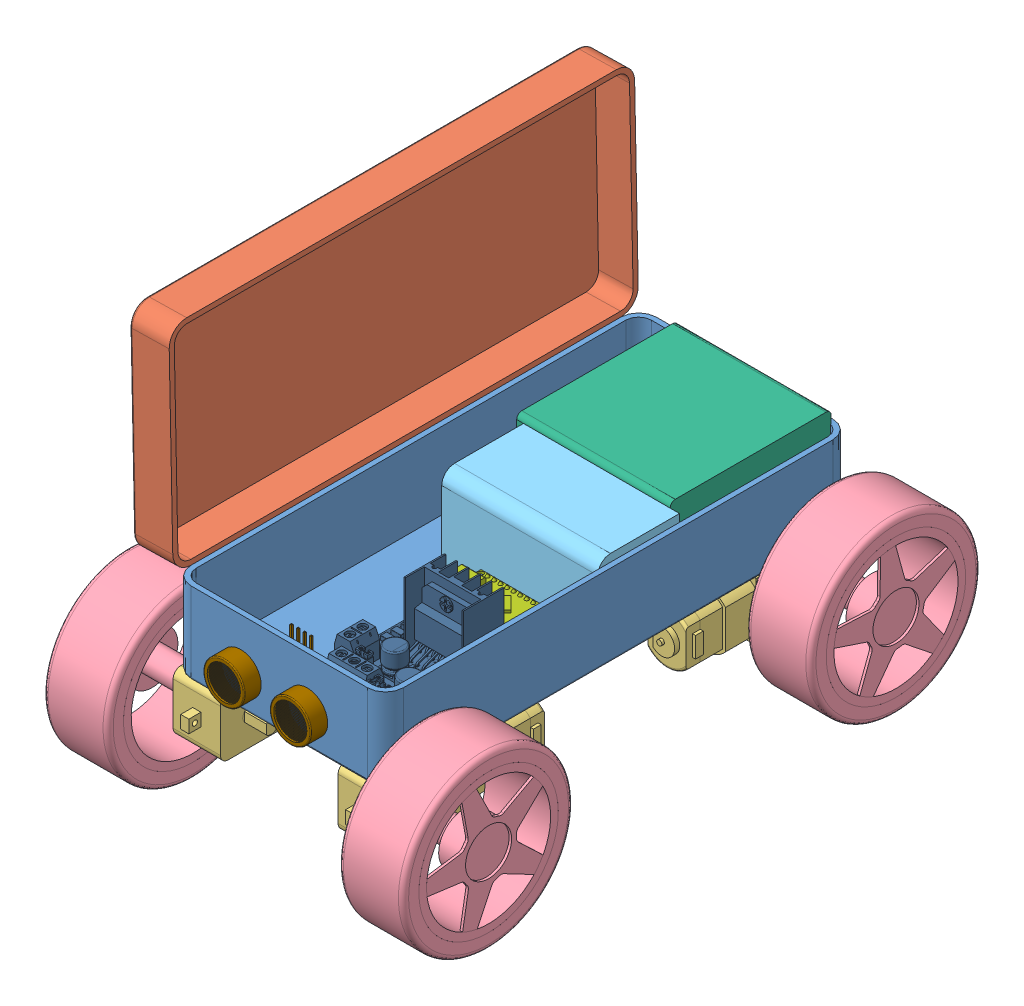
SolidWorks assembly Сборка1, configuration По умолчанию. Lengths in mm.
Overall size (141 168.35 238.58).
16 component instances, 10 part files, 33 mates.
Components (placement in the parent):
- Деталь1-1: Деталь1 [По умолчанию] at origin size (83 32 182)
- Деталь2-1: Деталь2 [По умолчанию] at (-84.679 114.983 0) x (-0.020229 0.999795 0) z (0 0 1) size (83 15.5 182)
- motor-1: motor [Predeterminado] at (-73.75 -11.35 -18.5) x (0 0 1) z (1 0 0) size (71.1 22.7 38)
- llanta-1: llanta [Predeterminado] at (-112 -11.35 -11.35) x (0 -0.972916 0.231159) z (-1 0 0) size (66.5 66.5 29)
- llanta-2: llanta [Predeterminado] at (29 -11.35 -11.35) x (0 0.314264 -0.949335) z (1 0 0) size (66.5 66.5 29)
- motor-2: motor [Predeterminado] at (-9.25 -11.35 -18.5) x (0 0 1) z (-1 0 0) size (71.1 22.7 38)
- motor-3: motor [Predeterminado] at (-9.25 -11.35 -163.5) x (0 0 -1) z (-1 0 0) size (71.1 22.7 38)
- llanta-3: llanta [Predeterminado] at (29 -11.35 -170.65) x (0 0.129067 -0.991636) z (1 0 0) size (66.5 66.5 29)
- motor-4: motor [Predeterminado] at (-73.75 -11.35 -163.5) x (0 0 -1) z (1 0 0) size (71.1 22.7 38)
- llanta-4: llanta [Predeterminado] at (-112 -11.35 -170.65) x (0 -0.02064 -0.999787) z (-1 0 0) size (66.5 66.5 29)
- Деталь3-1: Деталь3 [По умолчанию] at (-2 35 -85) x (0 1 0) z (0 0 1) size (33 61 32)
- Деталь4-1: Деталь4 [По умолчанию] at (-5.6654 2 -180) x (0 -1 0) z (0 0 -1) size (35 60 63)
- arduino-1: arduino [Valor predeterminado] at (-24.2753 10 -74.3614) size (45.18 17 17.78)
- hc05-1: hc05 [Varsayılan] at (-81 18.1 -175.0431) x (0 0 1) z (1 0 0) size (42.6 16.1 5.9)
- Sensor Ultrasonic-1: Sensor Ultrasonic [Predeterminado] at (-43.5678 12.17 -5.37) x (-1 0 0) z (0 0 1) size (45.42 26.14 17.7)
- L298N Dual H Bridge-1: L298N Dual H Bridge [Default] at (-29.5669 3.54 -42.6081) size (43.3 28.21 43.3)
Mates (geometry in assembly coordinates):
- Совпадение1: coincident aligned: line of Деталь1-1 through (-83 32 -175) axis (0 0 1); line of Деталь2-1 through (-83 32 -175) axis (0 0 1)
- Совпадение4: coincident: point of Деталь1-1; point of Деталь2-1
- Концентричный3: concentric anti-aligned: circle of motor-1; circle of llanta-1
- Совпадение5: coincident anti-aligned: plane of motor-1 through (-83 -19.7 -3) normal (-1 0 0); plane of llanta-1 through (-83 -11.35 -11.35) normal (1 0 0)
- Концентричный4: concentric anti-aligned: circle of llanta-2; circle of motor-2
- Совпадение6: coincident anti-aligned: plane of llanta-2 through (0 -11.35 -11.35) normal (-1 0 0); plane of motor-2 through (0 -3 -3) normal (1 0 0)
- Совпадение11: coincident anti-aligned: plane of Деталь1-1 through (-76 0 -7) normal (0 -1 0); plane of motor-2 through (0 0 -37) normal (0 1 0)
- Совпадение13: coincident aligned: plane of Деталь1-1 through (-7 32 0) normal (0 0 1); plane of motor-2 through (0 -19.7 0) normal (0 0 1)
- Совпадение14: coincident aligned: plane of Деталь1-1 through (0 32 -7) normal (1 0 0); plane of motor-2 through (0 -3 -3) normal (1 0 0)
- Совпадение15: coincident aligned: plane of Деталь1-1 through (-7 32 0) normal (0 0 1); plane of motor-1 through (-83 -3 0) normal (0 0 1)
- Совпадение16: coincident aligned: plane of Деталь1-1 through (-83 32 -7) normal (-1 0 0); plane of motor-1 through (-83 -19.7 -3) normal (-1 0 0)
- Совпадение17: coincident anti-aligned: plane of Деталь1-1 through (-76 0 -7) normal (0 -1 0); plane of motor-1 through (-83 0 -37) normal (0 1 0)
- Концентричный5: concentric anti-aligned: circle of motor-3; circle of llanta-3
- Совпадение18: coincident anti-aligned: plane of motor-3 through (0 -19.7 -179) normal (1 0 0); plane of llanta-3 through (0 -11.35 -170.65) normal (-1 0 0)
- Совпадение19: coincident aligned: plane of Деталь1-1 through (-7 32 -182) normal (0 0 -1); plane of motor-3 through (0 -3 -182) normal (0 0 -1)
- Совпадение20: coincident aligned: plane of Деталь1-1 through (0 32 -7) normal (1 0 0); plane of motor-3 through (0 -19.7 -179) normal (1 0 0)
- Совпадение21: coincident anti-aligned: plane of Деталь1-1 through (-76 0 -7) normal (0 -1 0); plane of motor-3 through (0 0 -145) normal (0 1 0)
- Концентричный6: concentric anti-aligned: circle of motor-4; circle of llanta-4
- Совпадение22: coincident anti-aligned: plane of motor-4 through (-83 -3 -179) normal (-1 0 0); plane of llanta-4 through (-83 -11.35 -170.65) normal (1 0 0)
- Совпадение32: coincident aligned: plane of Деталь1-1 through (-7 32 -182) normal (0 0 -1); plane of motor-4 through (-83 -19.7 -182) normal (0 0 -1)
- Совпадение33: coincident aligned: plane of Деталь1-1 through (-83 32 -7) normal (-1 0 0); plane of motor-4 through (-83 -3 -179) normal (-1 0 0)
- Совпадение34: coincident anti-aligned: plane of Деталь1-1 through (-76 0 -7) normal (0 -1 0); plane of motor-4 through (-83 0 -145) normal (0 1 0)
- Совпадение35: coincident anti-aligned: plane of Деталь1-1 through (-7 32 -180) normal (0 0 1); plane of Деталь4-1 through (-65.6654 4 -180) normal (0 0 -1)
- Совпадение36: coincident anti-aligned: plane of Деталь1-1 through (-76 2 -7) normal (0 1 0); plane of Деталь4-1 through (-65.6654 2 -178) normal (0 -1 0)
- Совпадение37: coincident anti-aligned: plane of Деталь3-1 through (-2 7 -112) normal (1 0 0); plane of Деталь1-1 through (-2 32 -7) normal (-1 0 0)
- Совпадение38: coincident anti-aligned: plane of Деталь1-1 through (-76 2 -7) normal (0 1 0); plane of Деталь3-1 through (-63 2 -85) normal (0 -1 0)
- Совпадение39: coincident anti-aligned: plane of Деталь3-1 through (-63 35 -117) normal (0 0 -1); plane of Деталь4-1 through (-65.6654 4 -117) normal (0 0 1)
- Совпадение40: coincident anti-aligned: plane of Деталь1-1 through (-7 32 -2) normal (0 0 -1); plane of Sensor Ultrasonic-1 through (-46.9778 4.05 -2) normal (0 0 1)
- Совпадение41: coincident anti-aligned: plane of Деталь1-1 through (-76 2 -7) normal (0 1 0); plane of Sensor Ultrasonic-1 through (-20.8578 2 -6.97) normal (0 -1 0)
- Совпадение42: coincident anti-aligned: plane of Деталь1-1 through (-76 2 -7) normal (0 1 0); plane of arduino-1 through (11.4947 2 -74.3614) normal (0 -1 0)
- Совпадение43: coincident anti-aligned: plane of Деталь1-1 through (-81 32 -7) normal (1 0 0); plane of hc05-1 through (-81 18.1 -175.0431) normal (-1 0 0)
- Совпадение44: coincident: plane of Деталь1-1 through (-76 2 -7) normal (0 1 0); line of hc05-1 through (-79.8 2 -137.5431) axis (0 0 -1)
- Совпадение45: coincident anti-aligned: plane of Деталь1-1 through (-76 2 -7) normal (0 1 0); plane of L298N Dual H Bridge-1 through (-29.5669 2 -42.6081) normal (0 -1 0)
